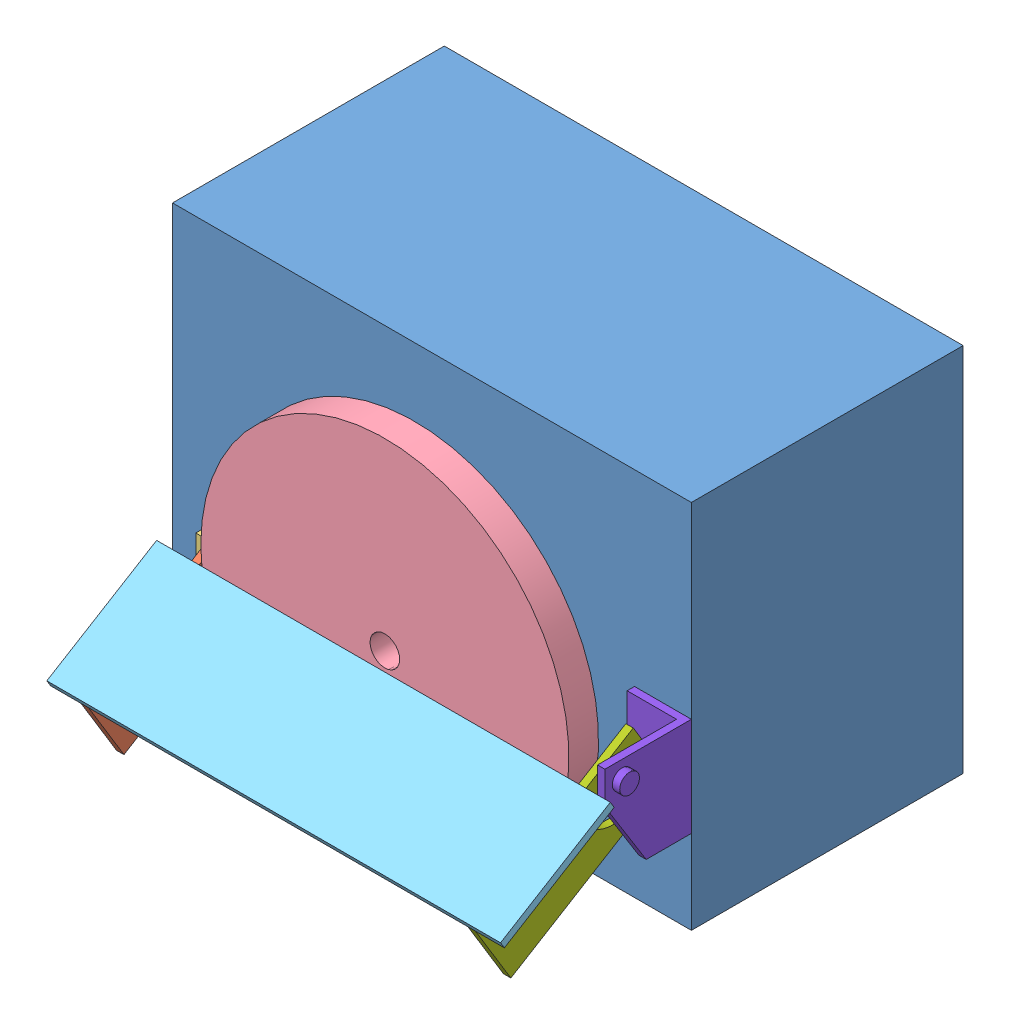
SolidWorks assembly Grinder Asem, configuration Default. Lengths in mm.
Overall size (228.27 202.54 196.25).
9 component instances, 9 part files, 17 mates.
Components (placement in the parent):
- Base Frame-1: Base Frame [Default] at origin size (210 20 175) (hidden)
- Grinder Housing-1: Grinder Housing [Default] at origin size (210 150 140)
- Left Angle Plate-1: Left Angle Plate [Default] at (6.4137 38.8922 -37.8453) x (1 0 0) z (0 -0.519465 0.854492) size (3 28 75)
- Left Face Bracket-1: Left Face Bracket [Default] at (0.4137 0 0) size (26 40 35)
- Plater-1: Plater [Default] at (-73.51 69.2361 1.0622) x (0.484618 -0.874726 0) z (0 0 1) size (149 149 12)
- Tool Rest-1: Tool Rest [Default] at (2.389 40.4061 -40.3355) x (1 0 0) z (0 -0.519465 0.854492) size (183.63 3 52)
- Right Slide-1: Right Slide [Default] at (-6 42.7877 -44.2531) x (1 0 0) z (0 -0.519465 0.854492) size (25 25 40)
- Right Angle-1: Right Angle [Default] at (-6 38.8922 -37.8453) x (1 0 0) z (0 -0.519465 0.854492) size (3 28 75)
- Right Face Bracket-1: Right Face Bracket [Default] at origin size (26 40 35)
Mates (geometry in assembly coordinates):
- Coincident25: coincident anti-aligned: plane of Grinder Housing-1 through (-105 170 22.5) normal (0 0 1); plane of Right Face Bracket-1 through (0 0 22.5) normal (0 0 -1)
- Coincident26: coincident anti-aligned: plane of Grinder Housing-1 through (-105 170 22.5) normal (0 0 1); plane of Left Face Bracket-1 through (0.4137 0 22.5) normal (0 0 -1)
- Coincident31: coincident aligned: plane of Left Face Bracket-1 through (0.4137 94 25.5) normal (0 1 0); plane of Right Face Bracket-1 through (105 94 25.5) normal (0 1 0)
- Parallel14: parallel aligned: plane of Grinder Housing-1 through (0 170 0) normal (0 1 0); plane of Right Face Bracket-1 through (105 94 25.5) normal (0 1 0)
- Distance10: distance = 3 mm: plane of Right Face Bracket-1 through (105 94 25.5) normal (0 1 0); cylinder of Grinder Housing-1 through (22 97 50.5) axis (0 0 -1) radius 4
- Coincident34: coincident aligned: plane of Grinder Housing-1 through (105 170 -87.5) normal (1 0 0); plane of Right Face Bracket-1 through (105 94 25.5) normal (1 0 0)
- Concentric8: concentric anti-aligned: cylinder of Right Angle-1 through (102 87 50.5) axis (-1 0 0) radius 4; cylinder of Right Face Bracket-1 through (99 87 50.5) axis (1 0 0) radius 4
- Coincident35: coincident aligned: plane of Right Angle-1 through (99 38.8922 -37.8453) normal (-1 0 0); plane of Right Face Bracket-1 through (99 87 50.5) normal (-1 0 0)
- Concentric9: concentric anti-aligned: cylinder of Left Angle Plate-1 through (-57.5863 87 50.5) axis (1 0 0) radius 4; cylinder of Left Face Bracket-1 through (-54.5863 87 50.5) axis (-1 0 0) radius 4
- Coincident36: coincident aligned: plane of Left Angle Plate-1 through (-54.5863 38.8922 -37.8453) normal (1 0 0); plane of Left Face Bracket-1 through (-54.5863 87 50.5) normal (1 0 0)
- Parallel15: parallel aligned: plane of Left Angle Plate-1 through (-57.5863 119.2144 10.9844) normal (0 0.854492 0.519465); plane of Right Angle-1 through (102 119.2144 10.9844) normal (0 0.854492 0.519465)
- Coincident38: coincident aligned: plane of Right Slide-1 through (-6 123.1099 4.5766) normal (0 0.854492 0.519465); plane of Right Angle-1 through (102 119.2144 10.9844) normal (0 0.854492 0.519465)
- Coincident39: coincident anti-aligned: plane of Right Slide-1 through (99 120.5464 3.0182) normal (1 0 0); plane of Right Angle-1 through (99 38.8922 -37.8453) normal (-1 0 0)
- Coincident40: coincident anti-aligned: plane of Tool Rest-1 through (2.389 120.7283 8.4942) normal (0 -0.854492 -0.519465); plane of Right Slide-1 through (-6 123.1099 4.5766) normal (0 0.854492 0.519465)
- Distance11: distance = 15 mm aligned: plane of Tool Rest-1 through (114 87.7423 62.7544) normal (1 0 0); plane of Right Slide-1 through (99 120.5464 3.0182) normal (1 0 0)
- Distance12: distance = 5 mm aligned: plane of Tool Rest-1 through (114 60.7301 107.188) normal (0 -0.519465 0.854492); plane of Right Slide-1 through (-6 60.764 101.3571) normal (0 -0.519465 0.854492)
- Coincident43: coincident anti-aligned: circle of Grinder Housing-1; cylinder of Plater-1 through (22 97 63.5622) axis (0 0 -1) radius 6
